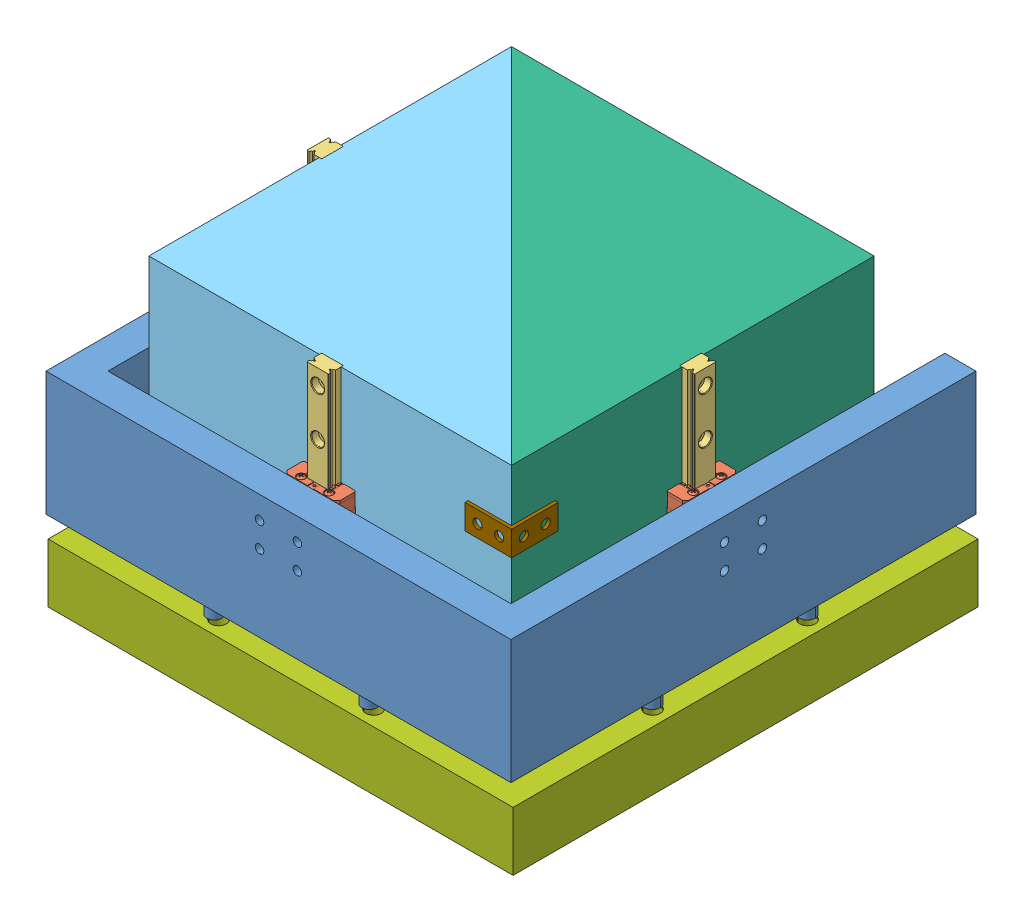
SolidWorks assembly full assem, configuration Default. Lengths in mm.
Overall size (150.68 97.73 150).
14 component instances, 9 part files, 34 mates.
Components (placement in the parent):
- rails-1: rails [Default] at (23.4642 89.2869 124.8226) size (150 45 150)
- MGN7C-1: MGN7C [MGN7C] at (23.5642 78.0369 186.5726) x (1 0 0) z (0 -1 0) size (17 6.5 23.31)
- MGN7C-2: MGN7C [MGN7C] at (-38.2858 78.0369 124.9226) x (0 0 -1) z (0 1 0) size (17 6.5 23.31)
- MGN7C-3: MGN7C [MGN7C] at (85.2142 78.0369 124.7226) x (0 0 -1) z (0 -1 0) size (17 6.5 23.31)
- MGN7 rail-1: MGN7 rail [150 mm] at (23.5605 121.4497 184.8763) x (1 0 0) z (0 -1 0) size (7 4.8 40)
- MGN7 rail-2: MGN7 rail [150 mm] at (-36.5895 121.4497 124.7263) x (0 0 1) z (0 -1 0) size (7 4.8 40)
- MGN7 rail-3: MGN7 rail [150 mm] at (83.7105 121.4497 124.7263) x (0 0 -1) z (0 -1 0) size (7 4.8 40)
- testmotor with holder-1: testmotor with holder [Default] at (23.5605 94.1497 124.7263) x (0 0 1) z (1 0 0) size (19.05 20.96 23.81)
- bottom right-1: bottom right [Default] at (82.0605 121.4497 66.2263) x (0 0 1) z (1 0 0) size (117 40 117)
- top left-1: top left [Default] at (82.0605 121.4497 66.2263) x (0 0 1) z (1 0 0) size (117 40 117)
- base (1)-1: base (1) [Default] at (-50.8576 23.7174 49.8226) x (0 0 1) z (-1 0 0) size (150 19 150)
- flywheel-2: flywheel [Default] at (24.1424 39.7174 124.8226) x (0.999729 0 -0.023273) z (0.023273 0 0.999729) size (55 3 55)
- L-bracket-1: L-bracket [Default] at (-35.4395 96.5345 72.7263) x (0 0 -1) z (0 1 0) size (15 15 8)
- L-bracket-2: L-bracket [Default] at (82.5605 96.5998 176.7263) x (0 0 1) z (0 1 0) size (15 15 8)
Mates (geometry in assembly coordinates):
- Coincident1: coincident anti-aligned: plane of rails-1 through (-41.5358 35.2869 189.8226) normal (0 0 -1); plane of MGN7C-1 through (23.5642 71.2869 189.8226) normal (0 0 1)
- Coincident2: coincident anti-aligned: circle of rails-1; circle of MGN7C-1
- Parallel1: parallel aligned: line of rails-1 through (-41.5358 89.2869 189.8226) axis (1 0 0); line of MGN7C-1 through (24.5268 89.2869 189.6226) axis (1 0 0)
- Coincident6: coincident aligned: circle of rails-1; circle of MGN7C-2
- Parallel2: parallel anti-aligned: line of rails-1 through (-41.5358 89.2869 49.8226) axis (0 0 1); line of MGN7C-2 through (-41.3358 89.2869 123.9601) axis (0 0 -1)
- Coincident7: coincident anti-aligned: circle of rails-1; circle of MGN7C-3
- Parallel3: parallel aligned: line of rails-1 through (88.4642 89.2869 189.8226) axis (0 0 -1); line of MGN7C-3 through (88.2642 89.2869 132.2226) axis (0 0 -1)
- Coincident28: coincident anti-aligned: plane of MGN7C-3 through (85.2142 89.2869 122.3863) normal (0 0 1); plane of MGN7 rail-3 through (84.3605 81.4497 122.3863) normal (0 0 -1)
- Coincident29: coincident anti-aligned: plane of bottom right-1 through (-34.9395 81.4497 66.2263) normal (0.707107 0 -0.707107); plane of top left-1 through (-34.9395 81.4497 66.2263) normal (-0.707107 0 0.707107)
- Coincident30: coincident aligned: line of bottom right-1 through (-34.9395 81.4497 66.2263) axis (0 1 0); line of top left-1 through (-34.9395 81.4497 66.2263) axis (0 1 0)
- Coincident31: coincident aligned: line of bottom right-1 through (-34.9395 121.4497 66.2263) axis (0.707107 0 0.707107); line of top left-1 through (-34.9395 121.4497 66.2263) axis (0.707107 0 0.707107)
- Coincident32: coincident anti-aligned: plane of MGN7 rail-2 through (-34.1895 81.4497 121.4263) normal (1 0 0); plane of bottom right-1 through (-34.1895 81.4497 121.2263) normal (-1 0 0)
- Coincident33: coincident anti-aligned: plane of MGN7 rail-2 through (-34.3895 81.4497 121.2263) normal (0 0 -1); plane of bottom right-1 through (-34.1895 81.4497 121.2263) normal (0 0 1)
- Coincident34: coincident anti-aligned: line of MGN7 rail-2 through (-34.1895 121.4497 121.4263) axis (0 0 1); line of bottom right-1 through (-34.1895 121.4497 128.2263) axis (0 0 -1)
- Coincident35: coincident anti-aligned: plane of MGN7 rail-3 through (81.3105 81.4497 128.0263) normal (-1 0 0); plane of top left-1 through (81.3105 81.4497 128.2263) normal (1 0 0)
- Coincident36: coincident anti-aligned: plane of MGN7 rail-3 through (81.5105 81.4497 121.2263) normal (0 0 -1); plane of top left-1 through (81.3105 81.4497 121.2263) normal (0 0 1)
- Coincident37: coincident anti-aligned: line of MGN7 rail-3 through (81.3105 81.4497 128.0263) axis (0 0 -1); line of top left-1 through (81.3105 81.4497 121.2263) axis (0 0 1)
- Coincident38: coincident anti-aligned: plane of MGN7 rail-1 through (20.2605 81.4497 182.4763) normal (0 0 -1); plane of bottom right-1 through (20.0605 81.4497 182.4763) normal (0 0 1)
- Coincident39: coincident anti-aligned: plane of MGN7 rail-1 through (27.0605 81.4497 182.6763) normal (1 0 0); plane of bottom right-1 through (27.0605 81.4497 182.4763) normal (-1 0 0)
- Coincident40: coincident anti-aligned: line of MGN7 rail-1 through (20.2605 81.4497 182.4763) axis (1 0 0); line of bottom right-1 through (27.0605 81.4497 182.4763) axis (-1 0 0)
- Coincident46: coincident anti-aligned: plane of testmotor with holder-1 through (23.5605 94.1497 124.7263) normal (0 1 0); plane of bottom right-1 through (82.0605 94.1497 66.2263) normal (0 -1 0)
- Coincident47: coincident aligned: line of testmotor with holder-1 through (7.6855 94.1497 134.2513) axis (0 0 -1); line of bottom right-1 through (7.6855 94.1497 134.2513) axis (0 0 -1)
- Coincident48: coincident aligned: line of testmotor with holder-1 through (23.5605 94.1497 115.2013) axis (-1 0 0); line of top left-1 through (23.5605 94.1497 115.2013) axis (-1 0 0)
- Parallel5: parallel anti-aligned: plane of MGN7C-2 through (-38.2858 89.2869 127.259) normal (0 0 -1); plane of MGN7 rail-2 through (-37.2395 81.4497 127.0664) normal (0 0 1)
- Coincident50: coincident anti-aligned: plane of MGN7C-1 through (25.9006 89.2869 186.5726) normal (-1 0 0); plane of MGN7 rail-1 through (25.9006 81.4497 185.5263) normal (1 0 0)
- Parallel6: parallel anti-aligned: plane of MGN7C-2 through (-38.2858 89.2869 122.5863) normal (0 0 1); plane of MGN7 rail-2 through (-37.2395 81.4497 122.3863) normal (0 0 -1)
- Coincident53: coincident anti-aligned: plane of base (1)-1 through (24.1424 39.7174 124.8226) normal (0 1 0); plane of flywheel-2 through (24.1424 39.7174 124.8226) normal (0 -1 0)
- Concentric2: concentric aligned: circle of base (1)-1; circle of flywheel-2
- Concentric3: concentric anti-aligned: circle of rails-1; circle of base (1)-1
- Concentric4: concentric anti-aligned: circle of rails-1; circle of base (1)-1
- Coincident54: coincident anti-aligned: plane of top left-1 through (82.0605 81.4497 66.2263) normal (0 0 -1); plane of L-bracket-1 through (-35.4395 104.5345 66.2263) normal (0 0 1)
- Coincident55: coincident anti-aligned: plane of bottom right-1 through (-34.9395 81.4497 66.2263) normal (-1 0 0); plane of L-bracket-1 through (-34.9395 104.5345 72.7263) normal (1 0 0)
- Coincident59: coincident anti-aligned: plane of top left-1 through (82.0605 81.4497 66.2263) normal (1 0 0); plane of L-bracket-2 through (82.0605 104.5998 176.7263) normal (-1 0 0)
- Coincident60: coincident anti-aligned: plane of bottom right-1 through (82.0605 81.4497 183.2263) normal (0 0 1); plane of L-bracket-2 through (82.5605 104.5998 183.2263) normal (0 0 -1)
